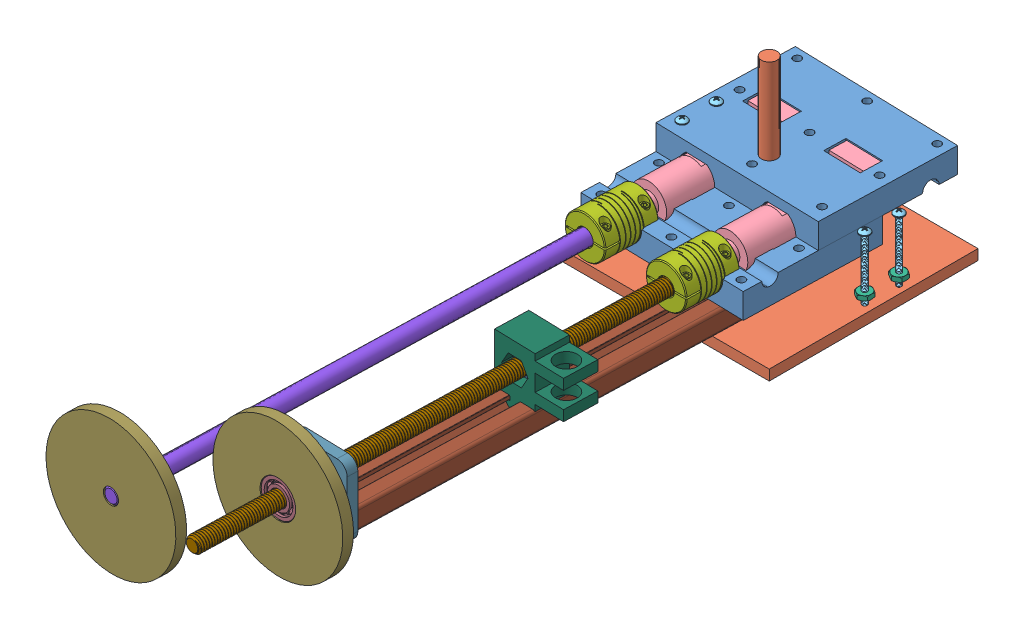
SolidWorks assembly Plotter, configuration Default. Lengths in mm.
Overall size (151.92 109.06 432.91).
26 component instances, 15 part files, 47 mates.
Components (placement in the parent):
- Motor Mount-1: Motor Mount [Default] at (0.5253 25.4 -19.0428) x (0.99962 0 0.027577) z (-0.027577 0 0.99962) size (101.6 15.24 82.55)
- Base-1: Base [Default] at origin size (127 107.95 127)
- Spacer-1: Spacer [Default] at (0 6.35 0) x (0.999889 0 0.014882) z (-0.014882 0 0.999889) size (25.4 19.05 25.4)
- Motor-1: Motor [Default] at (-24.4412 40.64 -35.1044) x (0.99962 0 0.027577) z (-0.027577 0 0.99962) size (21.97 25.4 95.5)
- Motor-2: Motor [Default] at (26.3395 40.64 -33.7034) x (0.99962 0 0.027577) z (-0.027577 0 0.99962) size (21.97 25.4 95.5)
- Motor Mount-2: Motor Mount [Default] at (-0.5253 55.88 19.0428) x (0.99962 0 0.027577) z (0.027577 0 -0.99962) size (101.6 15.24 82.55)
- Phillips Screw-1: Phillips Screw [90272A332] at (-44.0785 37.9603 8.9478) x (1 0 0) z (0 1 0) size (6.22 6.22 40.54)
- 0.125 Hex Nut-1: 0.125 Hex Nut [90480A006] at (-44.0785 24.0109 8.9478) size (7.94 3.28 9.17)
- 0.125 Hex Nut-2: 0.125 Hex Nut [90480A006] at (70.178 24.0109 12.0999) size (7.94 3.28 9.17)
- 0.125 Hex Nut-3: 0.125 Hex Nut [90480A006] at (-43.5181 24.0109 -11.3644) size (7.94 3.28 9.17)
- 0.125 Hex Nut-4: 0.125 Hex Nut [90480A006] at (70.7384 24.0109 -8.2123) size (7.94 3.28 9.17)
- Phillips Screw-2: Phillips Screw [90272A332] at (70.178 37.9603 12.0999) x (1 0 0) z (0 1 0) size (6.22 6.22 40.54)
- Phillips Screw-3: Phillips Screw [90272A332] at (-43.5181 37.9603 -11.3644) x (1 0 0) z (0 1 0) size (6.22 6.22 40.54)
- Phillips Screw-4: Phillips Screw [90272A332] at (70.7384 37.9603 -8.2123) x (1 0 0) z (0 1 0) size (6.22 6.22 40.54)
- Flexible Shaft Coupling-1: Flexible Shaft Coupling [2505K133] at (-27.3026 40.64 68.6152) x (0.99962 0 0.027577) z (-0.027577 0 0.99962) size (26.71 25.4 31.75)
- Flexible Shaft Coupling-2: Flexible Shaft Coupling [2505K133] at (23.4781 40.64 70.0161) x (0.999427 0.019626 0.027572) z (-0.027577 0 0.99962) size (26.71 25.4 31.75)
- Rotary Shaft-1: Rotary Shaft [1346K11] at (-31.2778 40.64 212.7053) x (-0.865838 0.499754 -0.023887) z (-0.027577 0 0.99962) size (9.53 9.53 304.8)
- Threaded Rod-1: Threaded Rod [3313N16] at (19.5029 40.64 214.1063) x (-0.027577 0 0.99962) z (0.908124 -0.417952 0.025053) size (307.78 9.66 11)
- .375 Hex Nut-1: .375 Hex Nut [95462A031] at (20.8515 40.64 165.2218) x (0.865696 -0.5 0.023883) z (-0.027577 0 0.99962) size (14.29 16.5 9.58)
- T-Slotted Framing Rail-1: T-Slotted Framing Rail [6575N215] at (21.7129 12.7 133.9997) x (0.99962 0 0.027577) z (-0.027577 0 0.99962) size (25.4 12.7 304.8)
- Our Wheel-1: Our Wheel [Default] at (-35.4805 40.64 365.0474) x (0.999239 -0.027577 0.027567) z (0.027567 0.99962 0.000761) size (81.28 6.35 81.28)
- Our Wheel-2: Our Wheel [Bearing] at (16.7011 40.64 315.6676) x (0.999239 -0.027577 0.027567) z (0.027567 0.99962 0.000761) size (81.28 6.35 81.28)
- Permanently Lubricated Ball Bearing-1: Permanently Lubricated Ball Bearing [2342K165] at (16.7886 40.64 312.4938) x (0.999239 -0.027577 0.027567) z (0.027577 0 -0.99962) size (22.23 22.23 5.56)
- Attachment-1: Attachment [Default] at (17.5101 12.7 286.3418) x (0.99962 0 0.027577) z (-0.027577 0 0.99962) size (38.1 44.45 6.35)
- Permanently Lubricated Ball Bearing-4: Permanently Lubricated Ball Bearing [2342K165] at (17.4225 40.64 289.5156) x (-0.174661 0.984617 -0.004819) z (-0.027577 0 0.99962) size (22.23 22.23 5.56)
- Pencil Holder-1: Pencil Holder [Default] at (20.8515 17.526 165.2218) x (0.99962 0 0.027577) z (-0.027577 0 0.99962) size (43.18 37.92 20.32)
Mates (geometry in assembly coordinates):
- Coincident1: coordinate: point of Base-1
- Concentric1: concentric: cylinder of Motor Mount-1 through (0 40.64 0) axis (0 1 0) radius 4.7625; cylinder of Base-1 through (0 107.95 0) axis (0 -1 0) radius 4.7625
- Concentric2: concentric aligned: cylinder of Base-1 through (0 107.95 0) axis (0 -1 0) radius 4.7625; cylinder of Spacer-1 through (0 25.4 0) axis (0 -1 0) radius 4.7625
- Coincident2: coincident anti-aligned: plane of Base-1 through (0 6.35 0) normal (0 1 0); plane of Spacer-1 through (0 6.35 0) normal (0 -1 0)
- Coincident3: coincident anti-aligned: plane of Motor Mount-1 through (-51.306 25.4 17.6418) normal (0 -1 0); plane of Spacer-1 through (0 25.4 0) normal (0 1 0)
- Coincident4: coincident anti-aligned: plane of Motor Mount-1 through (-32.4188 31.242 18.1629) normal (0 1 0); plane of Motor-1 through (-31.6756 31.242 20.8514) normal (0 -1 0)
- Width2: width: plane of Motor-1 through (-37.4866 40.64 -22.7594) normal (-0.027577 0 0.99962); plane of Motor-1 through (-38.6844 40.64 20.658) normal (0.027577 0 -0.99962); plane of Motor Mount-1 through (38.6109 40.64 -17.9921) normal (0.027577 0 -0.99962); plane of Motor Mount-1 through (37.5602 40.64 20.0935) normal (-0.027577 0 0.99962)
- Concentric5: concentric aligned: cylinder of Motor Mount-1 through (-25.9157 40.64 18.3423) axis (0.027577 0 -0.99962) radius 11.43; cylinder of Motor-1 through (-24.7914 40.64 -22.4092) axis (0.027577 0 -0.99962) radius 10.9855
- Coincident5: coincident anti-aligned: plane of Motor Mount-1 through (31.3681 31.242 19.9226) normal (0 1 0); plane of Motor-2 through (19.1051 31.242 22.2523) normal (0 -1 0)
- Width3: width: plane of Motor-2 through (38.6844 40.64 -20.658) normal (-0.027577 0 0.99962); plane of Motor-2 through (37.4866 40.64 22.7594) normal (0.027577 0 -0.99962); plane of Motor Mount-1 through (38.6109 40.64 -17.9921) normal (0.027577 0 -0.99962); plane of Motor Mount-1 through (37.5602 40.64 20.0935) normal (-0.027577 0 0.99962)
- Concentric6: concentric aligned: cylinder of Motor Mount-1 through (24.865 40.64 19.7432) axis (0.027577 0 -0.99962) radius 11.43; cylinder of Motor-2 through (25.9892 40.64 -21.0083) axis (0.027577 0 -0.99962) radius 10.9855
- Concentric7: concentric: cylinder of Base-1 through (0 107.95 0) axis (0 -1 0) radius 4.7625; cylinder of Motor Mount-2 through (0 40.64 0) axis (0 -1 0) radius 4.7625
- Coincident6: coincident anti-aligned: plane of Motor Mount-1 through (-51.306 40.64 17.6418) normal (0 1 0); plane of Motor Mount-2 through (-50.2553 40.64 -20.4437) normal (0 -1 0)
- Coincident7: coincident aligned: plane of Motor Mount-1 through (-51.306 25.4 17.6418) normal (-0.99962 0 -0.027577); plane of Motor Mount-2 through (-50.2553 55.88 -20.4437) normal (-0.99962 0 -0.027577)
- Coincident8: coincident anti-aligned: plane of Motor Mount-2 through (-50.2553 55.88 -20.4437) normal (0 1 0); plane of Phillips Screw-1 through (-41.1285 55.88 8.9478) normal (0 -1 0)
- Concentric8: concentric anti-aligned: cylinder of Motor Mount-2 through (-44.0785 40.64 8.9478) axis (0 -1 0) radius 2.3813; cylinder of Phillips Screw-1 through (-44.0785 58.1406 8.9478) axis (0 1 0) radius 1.5875
- Coincident9: coincident anti-aligned: plane of Motor Mount-1 through (-51.306 25.4 17.6418) normal (0 -1 0); plane of 0.125 Hex Nut-1 through (-48.0473 25.4 6.6565) normal (0 1 0)
- Concentric9: concentric anti-aligned: cylinder of Phillips Screw-1 through (-44.0785 58.1406 8.9478) axis (0 1 0) radius 1.5875; cylinder of 0.125 Hex Nut-1 through (-44.0785 25.4 8.9478) axis (0 -1 0) radius 1.5875
- Concentric11: concentric anti-aligned: cylinder of Motor-1 through (-27.075 40.64 60.3633) axis (0.027577 0 -0.99962) radius 4.7625; cylinder of Flexible Shaft Coupling-1 through (-26.8648 40.64 52.7462) axis (-0.027577 0 0.99962) radius 4.7625
- Coincident10: coincident aligned: plane of Motor-1 through (-26.8648 40.64 52.7462) normal (0.027577 0 -0.99962); plane of Flexible Shaft Coupling-1 through (-26.8648 40.64 52.7462) normal (0.027577 0 -0.99962)
- Concentric12: concentric anti-aligned: cylinder of Motor-2 through (23.7057 40.64 61.7642) axis (0.027577 0 -0.99962) radius 4.7625; cylinder of Flexible Shaft Coupling-2 through (23.9159 40.64 54.1471) axis (-0.027577 0 0.99962) radius 4.7625
- Coincident11: coincident aligned: plane of Motor-2 through (23.9159 40.64 54.1471) normal (0.027577 0 -0.99962); plane of Flexible Shaft Coupling-2 through (23.9159 40.64 54.1471) normal (0.027577 0 -0.99962)
- Coincident12: coincident anti-aligned: plane of Motor-1 through (-27.075 40.64 60.3633) normal (-0.027577 0 0.99962); plane of Rotary Shaft-1 through (-27.075 40.64 60.3633) normal (0.027577 0 -0.99962)
- Concentric13: concentric aligned: cylinder of Flexible Shaft Coupling-1 through (-27.7404 40.64 84.4841) axis (0.027577 0 -0.99962) radius 4.7625; cylinder of Rotary Shaft-1 through (-35.4805 40.64 365.0474) axis (0.027577 0 -0.99962) radius 4.7625
- Coincident13: coincident anti-aligned: plane of Motor-2 through (23.7057 40.64 61.7642) normal (-0.027577 0 0.99962); plane of Threaded Rod-1 through (23.7057 40.64 61.7642) normal (0.027577 0 -0.99962)
- Concentric14: concentric anti-aligned: cylinder of Flexible Shaft Coupling-2 through (23.0403 40.64 85.8851) axis (0.027577 0 -0.99962) radius 4.7625; cylinder of Threaded Rod-1 through (23.7057 40.64 61.7642) axis (-0.027577 0 0.99962) radius 4.7625
- Screw1: screw = 0.05 anti-aligned: axis of Threaded Rod-1 through (23.6729 40.64 62.9544) axis (-0.027577 0 0.99962); line of .375 Hex Nut-1 through (20.6711 40.64 171.7612) axis (0.027577 0 -0.99962)
- Coincident15: coincident anti-aligned: plane of Motor Mount-1 through (-51.306 25.4 17.6418) normal (0 -1 0); plane of T-Slotted Framing Rail-1 through (6.4653 25.4 286.0371) normal (0 1 0)
- Coincident17: coincident aligned: plane of Motor Mount-1 through (25.9157 40.64 -18.3423) normal (0.027577 0 -0.99962); plane of T-Slotted Framing Rail-1 through (14.8709 23.749 -18.647) normal (0.027577 0 -0.99962)
- Coincident20: coincident anti-aligned: plane of Motor Mount-2 through (-50.2553 55.88 -20.4437) normal (0 1 0); plane of T-Slotted Framing Rail-1 through (28.5819 55.88 286.6472) normal (0 -1 0)
- Concentric15: concentric anti-aligned: cylinder of Rotary Shaft-1 through (-35.4805 40.64 365.0474) axis (0.027577 0 -0.99962) radius 4.7625; cylinder of Our Wheel-1 through (-35.3054 40.64 358.6998) axis (-0.027577 0 0.99962) radius 4.7625
- Coincident22: coincident aligned: plane of Rotary Shaft-1 through (-35.4805 40.64 365.0474) normal (-0.027577 0 0.99962); plane of Our Wheel-1 through (-35.4805 40.64 365.0474) normal (-0.027577 0 0.99962)
- Concentric16: concentric anti-aligned: cylinder of Our Wheel-2 through (16.8762 40.64 309.32) axis (-0.027577 0 0.99962) radius 11.176; cylinder of Permanently Lubricated Ball Bearing-1 through (16.8652 40.64 309.7168) axis (0.027577 0 -0.99962) radius 11.1125
- Width5: width aligned: plane of Our Wheel-2 through (16.8762 40.64 309.32) normal (0.027577 0 -0.99962); plane of Our Wheel-2 through (16.7011 40.64 315.6676) normal (-0.027577 0 0.99962); plane of Permanently Lubricated Ball Bearing-1 through (16.5666 29.8094 309.7085) normal (0.027577 0 -0.99962); plane of Permanently Lubricated Ball Bearing-1 through (16.4133 29.8094 315.2627) normal (-0.027577 0 0.99962)
- Concentric17: concentric anti-aligned: cylinder of Threaded Rod-1 through (23.7057 40.64 61.7642) axis (-0.027577 0 0.99962) radius 4.7625; cylinder of Permanently Lubricated Ball Bearing-1 through (16.8652 40.64 309.7168) axis (0.027577 0 -0.99962) radius 4.7625
- Distance1: distance = 50.8 mm aligned: plane of Threaded Rod-1 through (15.3001 40.64 366.4483) normal (-0.027577 0 0.99962); plane of Our Wheel-2 through (16.7011 40.64 315.6676) normal (-0.027577 0 0.99962)
- InPlace1: in place: plane of ? through (6.4923 23.749 286.0378) normal (-0.027577 0 0.99962); plane of ? through (-7.8802 0 285.6413) normal (-0.027577 0 0.99962); moOrthogonalPlaneRef_w of ? through (6.4923 23.749 286.0378) normal (-0.027577 0 0.99962); plane of ? through (-7.8802 0 285.6413) normal (0 1 0); plane of ? through (6.4923 23.749 286.0378) normal (-0.027577 0 0.99962); plane of ? through (-7.8802 0 285.6413) normal (0.99962 0 0.027577); plane of T-Slotted Framing Rail-1 through (6.4653 23.749 286.0371) normal (-0.027577 0 0.99962); unknown of Attachment-1
- Coincident24: coincident aligned: plane of T-Slotted Framing Rail-1; plane of Attachment-1
- Coincident25: coincident aligned: moOrthogonalPlaneRef_w of T-Slotted Framing Rail-1 through (17.5101 12.7 286.3418) normal (0 1 0); plane of Part2^Plotter-1 through (17.5101 12.7 286.3418) normal (0 1 0)
- Coincident26: coincident anti-aligned: moOrthogonalPlaneRef_w of T-Slotted Framing Rail-1 through (17.5101 12.7 286.3418) normal (-0.99962 0 -0.027577); plane of Part2^Plotter-1 through (17.5101 12.7 286.3418) normal (0.99962 0 0.027577)
- Distance3: distance = 12.7 mm aligned: plane of Motor Mount-1 through (50.2553 25.4 20.4437) normal (0.99962 0 0.027577); plane of T-Slotted Framing Rail-1 through (30.2053 14.351 286.692) normal (0.99962 0 0.027577)
- Concentric21: concentric anti-aligned: cylinder of Part2^Plotter-1 through (17.335 40.64 292.6894) axis (0.027577 0 -0.99962) radius 12.7; cylinder of Permanently Lubricated Ball Bearing-4 through (17.3459 40.64 292.2926) axis (-0.027577 0 0.99962) radius 11.1125
- Width7: width aligned: plane of Part2^Plotter-1 through (17.335 12.7 292.6894) normal (-0.027577 0 0.99962); plane of Part2^Plotter-1 through (17.5101 12.7 286.3418) normal (0.027577 0 -0.99962); plane of Permanently Lubricated Ball Bearing-4 through (6.682 38.7469 291.9985) normal (-0.027577 0 0.99962); plane of Permanently Lubricated Ball Bearing-4 through (6.8352 38.7469 286.4443) normal (0.027577 0 -0.99962)
- Width8: width anti-aligned: plane of Pencil Holder-1 through (23.6182 22.5196 175.462) normal (0.99962 0 0.027577); plane of Pencil Holder-1 through (17.5245 22.5196 175.2939) normal (-0.99962 0 -0.027577); plane of T-Slotted Framing Rail-1 through (20.8108 25.4 286.4328) normal (-0.99962 0 -0.027577); plane of T-Slotted Framing Rail-1 through (14.2094 25.4 286.2507) normal (0.99962 0 0.027577)
- Coincident32: coincident anti-aligned: plane of T-Slotted Framing Rail-1 through (19.1659 17.526 286.3875) normal (0 1 0); plane of Pencil Holder-1 through (22.8159 17.526 175.4399) normal (0 -1 0)
- Parallel3: parallel anti-aligned: plane of .375 Hex Nut-1 through (24.8595 33.4962 169.5012) normal (0.865696 -0.5 0.023883); plane of Pencil Holder-1 through (24.6942 32.9882 175.4917) normal (-0.865696 0.5 -0.023883)
- Width9: width anti-aligned: plane of Pencil Holder-1 through (21.1317 17.526 155.0657) normal (0.027577 0 -0.99962); plane of Pencil Holder-1 through (20.5714 17.526 175.3779) normal (-0.027577 0 0.99962); plane of .375 Hex Nut-1 through (16.6137 47.7837 169.2737) normal (-0.027577 0 0.99962); plane of .375 Hex Nut-1 through (16.8436 47.7837 160.9425) normal (0.027577 0 -0.99962)
